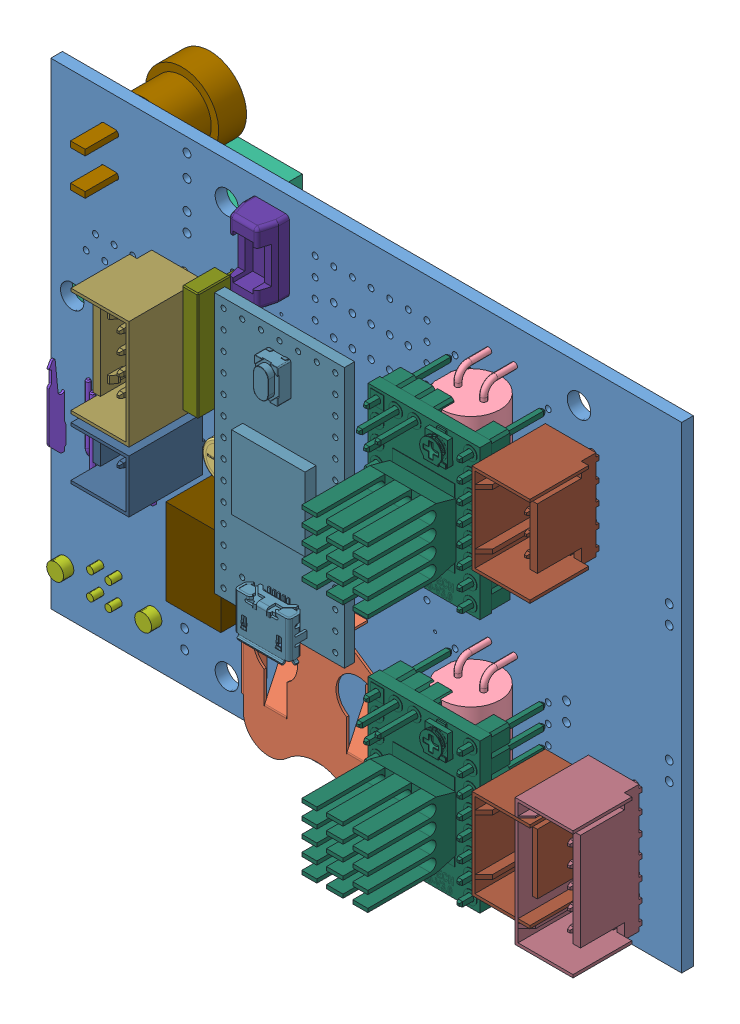
SolidWorks assembly CI EQ6, configuration Default. Lengths in mm.
Overall size (86 65 42.44).
21 component instances, 18 part files, 0 mates.
Components (placement in the parent):
- Board_CI_EQ6-1: Board_CI_EQ6 [Default] at origin size (86 65 1.59)
- CLIP_CR2032_RS_PRO_2378331-1: CLIP_CR2032_RS_PRO_2378331 [Default] at (39.7507 10.16 3.2) x (1 0 0) z (0 1 0) size (22.6 6.6 19.6)
- cappr-2.54_5.08-1: cappr-2.54_5.08 [Default] at (30.3175 36.0363 -2.286) size (5.3 5.59 9.46)
- D8x20coude-1: D8x20coude [Default] at (61.465 58.3538 4.2) x (1 0 0) z (0 -1 0) size (7.87 11 23.4)
- D8x20coude-2: D8x20coude [Default] at (61.465 24.0638 4.2) x (1 0 0) z (0 -1 0) size (7.87 11 23.4)
- diode_SMD_DO214_S5DC-13-F-1: diode_SMD_DO214_S5DC-13-F [Default] at (30.3175 45.2437 0) x (0 1 0) z (0 0 1) size (7.94 5.9 2.5)
- SS-90000-003-1: SS-90000-003 [Default] at (8 42.5 -1.5896) x (-1 0 0) z (0 0 -1) size (13.21 15.57 18.1)
- USB_B_droit-1: USB_B_droit [Default] at (8 7 -1.5896) x (-1 0 0) z (0 0 -1) size (14.3 11.1 19.1)
- M8_6pin_elbow_PCB-1: M8_6pin_elbow_PCB [Default] at (8 30.75 0.4104) x (1 0 0) z (0 -1 0) size (12.8 20.4 15.35)
- DC_55x25_droit-1: DC_55x25_droit [Default] at (8 58 -1.6896) x (0 1 0) z (0 0 -1) size (10 10 18)
- hdr-1x2t_2.54_sh7x8-1: hdr-1x2t_2.54_sh7x8 [Default] at (18.2563 31.75 -2) x (0 -1 0) z (0 0 1) size (7.21 7.9 14)
- hdr-1x4t_2.54_sh12x8-1: hdr-1x4t_2.54_sh12x8 [Default] at (73.8187 51.435 -2) x (0 1 0) z (0 0 1) size (12.29 7.9 14)
- hdr-1x4t_2.54_sh12x8-2: hdr-1x4t_2.54_sh12x8 [Default] at (73.8187 13.0175 -2) x (0 1 0) z (0 0 1) size (12.29 7.9 14)
- hdr-1x5t_2.54_sh15x8-1: hdr-1x5t_2.54_sh15x8 [Default] at (18.2562 43.815 -2) x (0 -1 0) z (0 0 1) size (14.83 7.9 14)
- hdr-1x6t_2.54_sh17x8-1: hdr-1x6t_2.54_sh17x8 [Default] at (79.6925 12.7 -2) x (0 1 0) z (0 0 1) size (17.37 7.9 14)
- Teensy_4.0_Assembly-1: Teensy_4.0_Assembly [Default] at (34.2563 76.18 0) x (0 1 0) z (1 0 0) size (36.75 4.12 17.7)
- TMC2130-V3.0-1: TMC2130-V3.0 [Default] at (61.465 48.6962 9) x (1 0 0) z (0 -1 0) size (15.24 22.13 20.32)
- TMC2130-V3.0-2: TMC2130-V3.0 [Default] at (61.465 14.06 9) x (1 0 0) z (0 -1 0) size (15.24 22.13 20.32)
- sip-6_14.7x2x2.54-1: sip-6_14.7x2x2.54 [Default] at (24.9237 45.72 -2) x (0 -1 0) z (0 0 1) size (14.8 2.16 7.95)
- suport_fusible_SMD-1: suport_fusible_SMD [Default] at (30.0037 57.7977 0) x (-1 0 0) z (0 1 0) size (5.03 3.81 9.73)
- TSR_1-2450-1: TSR_1-2450 [Default] at (29.74 24.9238 5.5) x (0 -1 0) z (-1 0 0) size (11.7 14.2 7.55)
